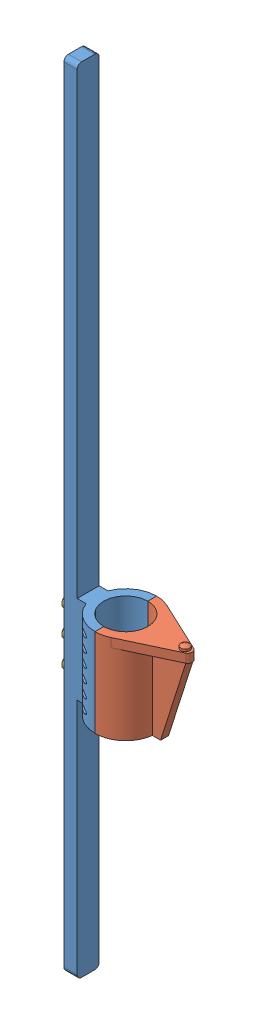
SolidWorks assembly sap montaj, configuration Default. Lengths in mm.
Overall size (568.89 4000 280).
17 component instances, 3 part files, 38 mates.
Components (placement in the parent):
- sap-1: sap [Default] at (549.0564 1205.0583 2442.1143) size (230.77 4000 280)
- no5-1: no5 [Default] at (549.0564 1605.0583 2442.1143) size (302.12 417 280)
- socket head cap screw_am-6: socket head cap screw_am [B18.3.1M - 16 x 2.0 x 80 Hex SHCS -- 44NHX] at (503.0564 1555.0583 2562.1143) size (96 24 24)
- socket head cap screw_am-7: socket head cap screw_am [B18.3.1M - 16 x 2.0 x 80 Hex SHCS -- 44NHX] at (503.0564 1495.0583 2562.1143) size (96 24 24)
- socket head cap screw_am-8: socket head cap screw_am [B18.3.1M - 16 x 2.0 x 80 Hex SHCS -- 44NHX] at (503.0564 1375.0583 2562.1143) x (1 0 0) z (0 0.323103 0.946364) size (96 24 24)
- socket head cap screw_am-9: socket head cap screw_am [B18.3.1M - 16 x 2.0 x 80 Hex SHCS -- 44NHX] at (503.0564 1255.0583 2562.1143) size (96 24 24)
- socket head cap screw_am-10: socket head cap screw_am [B18.3.1M - 16 x 2.0 x 80 Hex SHCS -- 44NHX] at (503.0564 1315.0583 2322.1143) size (96 24 24)
- socket head cap screw_am-11: socket head cap screw_am [B18.3.1M - 16 x 2.0 x 80 Hex SHCS -- 44NHX] at (503.0564 1435.0583 2562.1143) x (1 0 0) z (0 0 -1) size (96 24 24)
- socket head cap screw_am-12: socket head cap screw_am [B18.3.1M - 16 x 2.0 x 80 Hex SHCS -- 44NHX] at (503.0564 1255.0583 2322.1143) size (96 24 24)
- socket head cap screw_am-13: socket head cap screw_am [B18.3.1M - 16 x 2.0 x 80 Hex SHCS -- 44NHX] at (503.0564 1375.0583 2322.1143) size (96 24 24)
- socket head cap screw_am-14: socket head cap screw_am [B18.3.1M - 16 x 2.0 x 80 Hex SHCS -- 44NHX] at (503.0564 1315.0583 2562.1143) x (1 0 0) z (0 -0.989637 0.143592) size (96 24 24)
- socket head cap screw_am-15: socket head cap screw_am [B18.3.1M - 16 x 2.0 x 80 Hex SHCS -- 44NHX] at (503.0564 1555.0583 2322.1143) size (96 24 24)
- socket head cap screw_am-16: socket head cap screw_am [B18.3.1M - 16 x 2.0 x 80 Hex SHCS -- 44NHX] at (503.0564 1495.0583 2322.1143) size (96 24 24)
- socket head cap screw_am-17: socket head cap screw_am [B18.3.1M - 16 x 2.0 x 80 Hex SHCS -- 44NHX] at (503.0564 1435.0583 2322.1143) size (96 24 24)
- socket head cap screw_am-19: socket head cap screw_am [B18.3.1M - 36 x 4.0 x 80 Hex SHCS -- 80NHX] at (282.2894 1285.0583 2442.1143) size (116 54 54)
- socket head cap screw_am-18: socket head cap screw_am [B18.3.1M - 36 x 4.0 x 80 Hex SHCS -- 80NHX] at (282.2894 1525.0583 2442.1143) x (1 0 0) z (0 0.987098 -0.160117) size (116 54 54)
- socket head cap screw_am-20: socket head cap screw_am [B18.3.1M - 36 x 4.0 x 80 Hex SHCS -- 80NHX] at (282.2894 1405.0583 2442.1143) x (1 0 0) z (0 0.982449 -0.18653) size (116 54 54)
Mates (geometry in assembly coordinates):
- Çakışık3: coincident anti-aligned: line of sap-1 through (549.0564 1605.0583 2582.1143) axis (0 -1 0); line of no5-1 through (549.0564 1205.0583 2582.1143) axis (0 1 0)
- Çakışık4: coincident aligned: line of sap-1 through (549.0564 1605.0583 2542.1143) axis (0 0 1); line of no5-1 through (549.0564 1605.0583 2542.1143) axis (0 0 1)
- Eş Merkezli1: concentric anti-aligned: cylinder of sap-1 through (349.0564 1555.0583 2562.1143) axis (1 0 0) radius 12; cylinder of socket head cap screw_am-6 through (471.3064 1555.0583 2562.1143) axis (-1 0 0) radius 8
- Çakışık5: coincident anti-aligned: plane of sap-1 through (519.0564 1555.0583 2562.1143) normal (-1 0 0); plane of socket head cap screw_am-6 through (519.0564 1567.0583 2562.1143) normal (1 0 0)
- Eş Merkezli2: concentric anti-aligned: cylinder of sap-1 through (349.0564 1495.0583 2562.1143) axis (1 0 0) radius 12; cylinder of socket head cap screw_am-7 through (471.3064 1495.0583 2562.1143) axis (-1 0 0) radius 8
- Çakışık6: coincident anti-aligned: plane of sap-1 through (519.0564 1495.0583 2562.1143) normal (-1 0 0); plane of socket head cap screw_am-7 through (519.0564 1507.0583 2562.1143) normal (1 0 0)
- Eş Merkezli3: concentric anti-aligned: cylinder of sap-1 through (519.0564 1435.0583 2562.1143) axis (1 0 0) radius 8; cylinder of socket head cap screw_am-11 through (471.3064 1435.0583 2562.1143) axis (-1 0 0) radius 8
- Çakışık7: coincident anti-aligned: plane of sap-1 through (519.0564 1435.0583 2562.1143) normal (-1 0 0); plane of socket head cap screw_am-11 through (519.0564 1423.0583 2562.1143) normal (1 0 0)
- Eş Merkezli4: concentric anti-aligned: cylinder of sap-1 through (519.0564 1375.0583 2562.1143) axis (1 0 0) radius 8; cylinder of socket head cap screw_am-8 through (471.3064 1375.0583 2562.1143) axis (-1 0 0) radius 12
- Eş Merkezli5: concentric anti-aligned: cylinder of sap-1 through (519.0564 1375.0583 2562.1143) axis (1 0 0) radius 8; cylinder of socket head cap screw_am-8 through (471.3064 1375.0583 2562.1143) axis (-1 0 0) radius 8
- Eş Merkezli6: concentric anti-aligned: cylinder of sap-1 through (349.0564 1375.0583 2562.1143) axis (1 0 0) radius 12; cylinder of socket head cap screw_am-8 through (471.3064 1375.0583 2562.1143) axis (-1 0 0) radius 12
- Eş Merkezli7: concentric anti-aligned: cylinder of sap-1 through (519.0564 1375.0583 2562.1143) axis (1 0 0) radius 8; cylinder of socket head cap screw_am-8 through (471.3064 1375.0583 2562.1143) axis (-1 0 0) radius 12
- Eş Merkezli8: concentric anti-aligned: cylinder of sap-1 through (519.0564 1375.0583 2562.1143) axis (1 0 0) radius 8; cylinder of socket head cap screw_am-8 through (471.3064 1375.0583 2562.1143) axis (-1 0 0) radius 12
- Eş Merkezli9: concentric aligned: cylinder of no5-1 through (599.0564 1375.0583 2562.1143) axis (-1 0 0) radius 8; cylinder of socket head cap screw_am-8 through (471.3064 1375.0583 2562.1143) axis (-1 0 0) radius 8
- Çakışık9: coincident anti-aligned: plane of sap-1 through (519.0564 1375.0583 2562.1143) normal (-1 0 0); plane of socket head cap screw_am-8 through (519.0564 1386.4146 2558.2371) normal (1 0 0)
- Eş Merkezli10: concentric anti-aligned: cylinder of sap-1 through (349.0564 1315.0583 2562.1143) axis (1 0 0) radius 12; cylinder of socket head cap screw_am-14 through (471.3064 1315.0583 2562.1143) axis (-1 0 0) radius 8
- Çakışık15: coincident anti-aligned: plane of sap-1 through (519.0564 1315.0583 2562.1143) normal (-1 0 0); plane of socket head cap screw_am-14 through (519.0564 1316.7814 2573.9899) normal (1 0 0)
- Eş Merkezli11: concentric anti-aligned: cylinder of sap-1 through (349.0564 1255.0583 2562.1143) axis (1 0 0) radius 12; cylinder of socket head cap screw_am-9 through (471.3064 1255.0583 2562.1143) axis (-1 0 0) radius 8
- Çakışık16: coincident anti-aligned: plane of sap-1 through (519.0564 1255.0583 2562.1143) normal (-1 0 0); plane of socket head cap screw_am-9 through (519.0564 1267.0583 2562.1143) normal (1 0 0)
- Eş Merkezli12: concentric anti-aligned: cylinder of sap-1 through (349.0564 1555.0583 2322.1143) axis (1 0 0) radius 12; cylinder of socket head cap screw_am-15 through (471.3064 1555.0583 2322.1143) axis (-1 0 0) radius 8
- Çakışık17: coincident anti-aligned: plane of sap-1 through (519.0564 1555.0583 2322.1143) normal (-1 0 0); plane of socket head cap screw_am-15 through (519.0564 1567.0583 2322.1143) normal (1 0 0)
- Eş Merkezli13: concentric anti-aligned: cylinder of sap-1 through (349.0564 1495.0583 2322.1143) axis (1 0 0) radius 12; cylinder of socket head cap screw_am-16 through (471.3064 1495.0583 2322.1143) axis (-1 0 0) radius 8
- Çakışık18: coincident anti-aligned: plane of sap-1 through (519.0564 1495.0583 2322.1143) normal (-1 0 0); plane of socket head cap screw_am-16 through (519.0564 1507.0583 2322.1143) normal (1 0 0)
- Eş Merkezli14: concentric anti-aligned: cylinder of sap-1 through (349.0564 1435.0583 2322.1143) axis (1 0 0) radius 12; cylinder of socket head cap screw_am-17 through (471.3064 1435.0583 2322.1143) axis (-1 0 0) radius 8
- Çakışık19: coincident anti-aligned: plane of sap-1 through (519.0564 1435.0583 2322.1143) normal (-1 0 0); plane of socket head cap screw_am-17 through (519.0564 1447.0583 2322.1143) normal (1 0 0)
- Çakışık20: coincident anti-aligned: plane of sap-1 through (519.0564 1315.0583 2322.1143) normal (-1 0 0); plane of socket head cap screw_am-10 through (519.0564 1327.0583 2322.1143) normal (1 0 0)
- Çakışık21: coincident anti-aligned: plane of sap-1 through (519.0564 1315.0583 2322.1143) normal (-1 0 0); plane of socket head cap screw_am-10 through (519.0564 1327.0583 2322.1143) normal (1 0 0)
- Eş Merkezli16: concentric anti-aligned: cylinder of sap-1 through (349.0564 1315.0583 2322.1143) axis (1 0 0) radius 12; cylinder of socket head cap screw_am-10 through (471.3064 1315.0583 2322.1143) axis (-1 0 0) radius 8
- Eş Merkezli17: concentric anti-aligned: cylinder of sap-1 through (349.0564 1375.0583 2322.1143) axis (1 0 0) radius 12; cylinder of socket head cap screw_am-13 through (471.3064 1375.0583 2322.1143) axis (-1 0 0) radius 8
- Çakışık22: coincident anti-aligned: plane of sap-1 through (519.0564 1375.0583 2322.1143) normal (-1 0 0); plane of socket head cap screw_am-13 through (519.0564 1387.0583 2322.1143) normal (1 0 0)
- Eş Merkezli18: concentric anti-aligned: cylinder of sap-1 through (349.0564 1255.0583 2322.1143) axis (1 0 0) radius 12; cylinder of socket head cap screw_am-12 through (471.3064 1255.0583 2322.1143) axis (-1 0 0) radius 8
- Çakışık23: coincident anti-aligned: plane of sap-1 through (519.0564 1255.0583 2322.1143) normal (-1 0 0); plane of socket head cap screw_am-12 through (519.0564 1267.0583 2322.1143) normal (1 0 0)
- Eş Merkezli19: concentric aligned: cylinder of sap-1 through (398.2894 1525.0583 2442.1143) axis (-1 0 0) radius 18; cylinder of socket head cap screw_am-18 through (250.5394 1525.0583 2442.1143) axis (-1 0 0) radius 18
- Çakışık24: coincident anti-aligned: plane of sap-1 through (318.2894 125.0583 2412.1143) normal (-1 0 0); plane of socket head cap screw_am-18 through (318.2894 1520.7351 2415.4627) normal (1 0 0)
- Eş Merkezli20: concentric aligned: cylinder of sap-1 through (398.2894 1405.0583 2442.1143) axis (-1 0 0) radius 18; cylinder of socket head cap screw_am-20 through (250.5394 1405.0583 2442.1143) axis (-1 0 0) radius 18
- Çakışık25: coincident anti-aligned: plane of sap-1 through (318.2894 125.0583 2412.1143) normal (-1 0 0); plane of socket head cap screw_am-20 through (318.2894 1400.0219 2415.5882) normal (1 0 0)
- Eş Merkezli21: concentric aligned: cylinder of sap-1 through (398.2894 1285.0583 2442.1143) axis (-1 0 0) radius 18; cylinder of socket head cap screw_am-19 through (250.5394 1285.0583 2442.1143) axis (-1 0 0) radius 18
- Çakışık26: coincident anti-aligned: plane of sap-1 through (318.2894 125.0583 2412.1143) normal (-1 0 0); plane of socket head cap screw_am-19 through (318.2894 1312.0583 2442.1143) normal (1 0 0)
